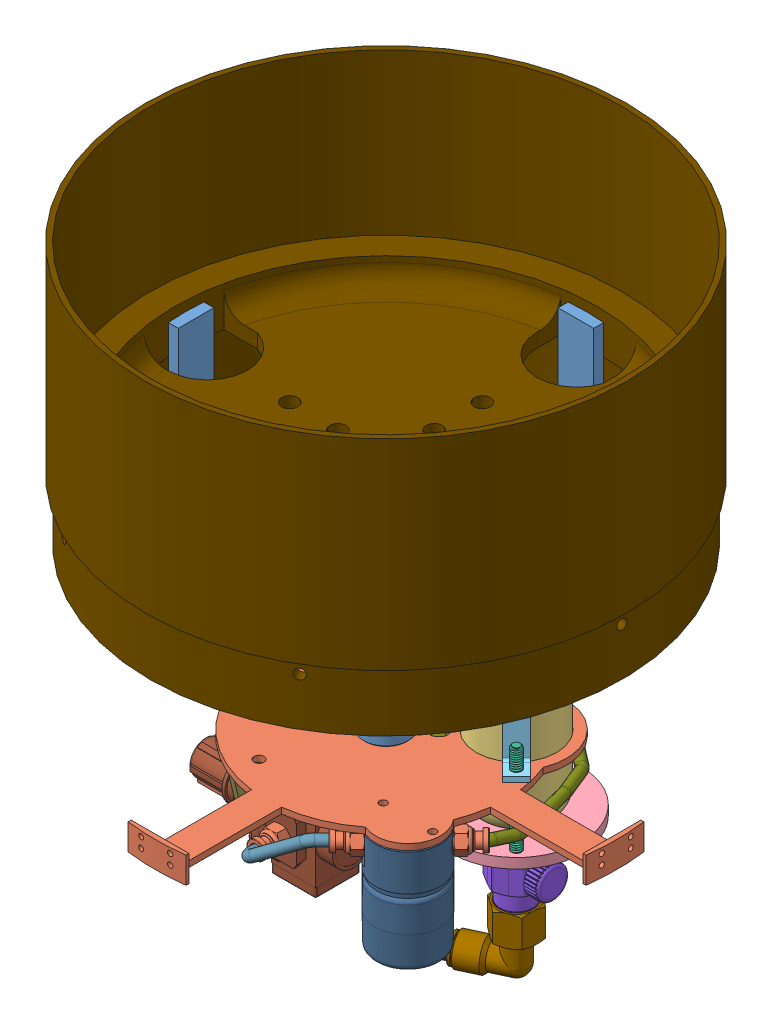
SolidWorks assembly 10004-R01_RECOVERY_SYSTEM, configuration Default. Lengths in mm.
Overall size (304.8 403.35 304.8).
35 component instances, 21 part files, 66 mates.
Components (placement in the parent):
- 16007-RO01_ROUND_BODY_AIR_CYLINDER-2: 16007-RO01_ROUND_BODY_AIR_CYLINDER [6498K062] at (101.6 47.752 101.6) x (0 -1 0) z (-0.809092 0 -0.587682) size (127.62 28.45 28.45)
- 16002-R01_BRASS_PUSH_TO_CONNECT_TUBE_FITTING_FOR_AIR (1)-1: 16002-R01_BRASS_PUSH_TO_CONNECT_TUBE_FITTING_FOR_AIR (1) [51025K177] at (86.3697 13.462 90.5375) x (-0.809092 0 -0.587682) z (-0.508948 -0.5 0.700694) size (22.87 14.66 12.7)
- 14019-R01_RECOVERY_PRESSURE_TANK (1)-1: 14019-R01_RECOVERY_PRESSURE_TANK (1) [Default] at (142.875 76.454 60.325) x (-0.286418 0 0.958105) z (0.958105 0 0.286418) size (50 133 50)
- 14020-R01_RECOVERY_PRESSURE_TANK_BULKHEAD (1)-7: 14020-R01_RECOVERY_PRESSURE_TANK_BULKHEAD (1) [Default] at (142.875 -41.1336 60.325) x (-0.707107 0 -0.707107) z (0.707107 0 -0.707107) size (82.15 6.35 82.15)
- 14021-R01_RECOVERY_PRESSURE_TANK__MOUNT-1: 14021-R01_RECOVERY_PRESSURE_TANK__MOUNT [Default] at (167.4293 6.35 84.8793) x (0.707107 0 0.707107) z (-0.707107 0 0.707107) size (82.15 73.28 12.7)
- 16005-R01_THREADED ROD-1: 16005-R01_THREADED ROD [98750A021] at (167.4293 -9.3836 84.8793) x (0 1 0) z (0 0 1) size (64.96 6.43 6.7)
- 16005-R01_THREADED ROD-2: 16005-R01_THREADED ROD [98750A021] at (118.3207 -9.3836 35.7707) x (0 1 0) z (0 0 1) size (64.96 6.43 6.7)
- 16005-R01_THREADED ROD-3: 16005-R01_THREADED ROD [98750A021] at (118.3207 -9.3836 84.8793) x (0 1 0) z (0 0 1) size (64.96 6.43 6.7)
- 16006-R01_NYLON-INSERT_NUTLOCK-1: 16006-R01_NYLON-INSERT_NUTLOCK [97135A210] at (167.4293 9.525 84.8793) x (0.707107 0 0.707107) z (-0.707107 0 0.707107) size (11.11 8.13 12.83) (hidden)
- 16006-R01_NYLON-INSERT_NUTLOCK-2: 16006-R01_NYLON-INSERT_NUTLOCK [97135A210] at (118.3207 6.35 84.8793) x (0.965926 0 -0.258819) z (0.258819 0 0.965926) size (11.11 8.13 12.83)
- 16006-R01_NYLON-INSERT_NUTLOCK-3: 16006-R01_NYLON-INSERT_NUTLOCK [97135A210] at (118.3207 9.525 35.7707) x (0.965926 0 -0.258819) z (0.258819 0 0.965926) size (11.11 8.13 12.83)
- 16010-R01_ON_OFF_VALVE_FOR_RECOVERY_PRESSURE_TANK-1: 16010-R01_ON_OFF_VALVE_FOR_RECOVERY_PRESSURE_TANK [Default] at (142.875 -56.546 60.325) size (40 51.5 30.85)
- 16009-R01_PUSH_TO_CONNECT_TUBE_FITTING_FOR_AIR_90_DEGREE_SWIVEL-1: 16009-R01_PUSH_TO_CONNECT_TUBE_FITTING_FOR_AIR_90_DEGREE_SWIVEL [5225K893] at (142.875 -86.546 60.325) x (0.422618 0 0.906308) z (0 1 0) size (24.39 44.36 43.87)
- 16002-R01_BRASS_PUSH_TO_CONNECT_TUBE_FITTING_FOR_AIR (1)-5: 16002-R01_BRASS_PUSH_TO_CONNECT_TUBE_FITTING_FOR_AIR (1) [51025K177] at (91.275 -29.083 162.3949) x (0 0 1) z (0 -1 0) size (22.87 14.66 12.7)
- 16002-R01_BRASS_PUSH_TO_CONNECT_TUBE_FITTING_FOR_AIR (1)-7: 16002-R01_BRASS_PUSH_TO_CONNECT_TUBE_FITTING_FOR_AIR (1) [51025K177] at (91.275 -29.083 113.1951) x (0 0 -1) z (0.866025 0.5 0) size (22.87 14.66 12.7)
- 16003-R01_SURE-SEAL_STAINLESS STEEL_SOLENOID_VALVE (1)-3: 16003-R01_SURE-SEAL_STAINLESS STEEL_SOLENOID_VALVE (1) [4639K743] at (156.6334 -6.1976 142.7687) x (-0.706999 0 -0.707214) z (-0.707214 0 0.706999) size (69.98 72.57 41.1)
- 16004-R01_AIR_REGULATOR _WITH_BUILT-IN_PRESSURE_GAUGE (1)-3: 16004-R01_AIR_REGULATOR _WITH_BUILT-IN_PRESSURE_GAUGE (1) [8812K51] at (91.275 -29.083 137.795) x (0 0 -1) z (0 -1 0) size (40.79 94 58.3)
- 14022-R01_BRACKET_FOR_AIR_REGULATOR-1: 14022-R01_BRACKET_FOR_AIR_REGULATOR [Default] at (63.5 -29.083 137.795) x (0 -1 0) z (0 0 1) size (50.93 28.57 53.34)
- 16002-R01_BRASS_PUSH_TO_CONNECT_TUBE_FITTING_FOR_AIR (1)-9: 16002-R01_BRASS_PUSH_TO_CONNECT_TUBE_FITTING_FOR_AIR (1) [51025K177] at (174.4053 -6.1976 125.0022) x (0.707214 0 -0.706999) z (0.612279 0.5 0.612466) size (22.87 14.66 12.7)
- 16002-R01_BRASS_PUSH_TO_CONNECT_TUBE_FITTING_FOR_AIR (1)-10: 16002-R01_BRASS_PUSH_TO_CONNECT_TUBE_FITTING_FOR_AIR (1) [51025K177] at (139.6518 -6.1976 159.7451) x (-0.707214 0 0.706999) z (-0.612279 0.5 -0.612466) size (22.87 14.66 12.7)
- 16008-R01_PUSH_TO_CONNECT_TUBE_FITTING_FOR_AIR_STRAIGHT_ADAPTER-2: 16008-R01_PUSH_TO_CONNECT_TUBE_FITTING_FOR_AIR_STRAIGHT_ADAPTER [5779K719] at (92.2124 -79.6146 83.9494) x (-0.906308 0 0.422618) z (0 -1 0) size (16 16 50.04)
- Tube_4-10004-R01_Recovery_System (4)-1: Tube_4-10004-R01_Recovery_System (4) [Default] at origin size (71.08 37.36 56.07)
  - straight fitting-1: straight fitting [.25 TUBE X .25 NPT] at (148.1269 -6.1976 151.2726) x (0.707214 0 -0.706999) z (0.706999 0 0.707214) size (37.85 16.5 14.29) (hidden)
  - Tube-250X020^Tube_4-10004-R01_Recovery_System (4)-1: Tube-250X020^Tube_4-10004-R01_Recovery_System (4) [Tube .250in OD X .020in Wall] at (132.1396 -6.1976 167.255) x (0.577233 0.577409 0.577409) z (-0.707214 0 0.706999) size (39.07 13.45 39.63) (virtual)
- Tube_5-10004-R01_Recovery_System (4)-1: Tube_5-10004-R01_Recovery_System (4) [Default] at origin size (54.15 57.91 51.01)
  - straight fitting-1: straight fitting [.25 TUBE X .25 NPT] at (91.275 -29.083 131.7828) x (0 0 1) z (-1 0 0) size (37.85 16.5 14.29) (hidden)
  - Tube-250X020^Tube_5-10004-R01_Recovery_System (4)-1: Tube-250X020^Tube_5-10004-R01_Recovery_System (4) [Tube .250in OD X .020in Wall] at (91.275 -29.083 109.1768) x (0.707107 0.707107 0) z (0 0 -1) size (37.62 38.95 28.4) (virtual)
- Tube_7-10004-R01_Recovery_System (4)-1: Tube_7-10004-R01_Recovery_System (4) [Default] at origin size (179.67 88.63 166.88)
  - straight fitting-1: straight fitting [.25 TUBE X .25 NPT] at (97.0152 13.462 98.2699) x (0.809092 0 0.587682) z (-0.587682 0 0.809092) size (37.85 16.5 14.29) (hidden)
  - Tube-250X020^Tube_7-10004-R01_Recovery_System (4)-1: Tube-250X020^Tube_7-10004-R01_Recovery_System (4) [Tube .250in OD X .020in Wall] at (78.7249 13.462 84.9847) x (-0.456869 0.628995 0.628995) z (-0.809092 0 -0.587682) size (87.39 43.3 152.94) (virtual)
- Tube_11-10004-R01_Recovery_System (4)-005-1: Tube_11-10004-R01_Recovery_System (4)-005 [Default] at origin size (62.6 58.78 70.76)
  - Tube-500X010_3^Tube_11-10004-R01_Recovery_System (4)-005-1: Tube-500X010_3^Tube_11-10004-R01_Recovery_System (4)-005 [Tube .500in OD X .010in Wall] at (124.2957 -120.546 68.9887) x (0.313146 0.671543 0.671543) z (-0.906308 0 0.422618) size (40.26 42.84 41.75) (virtual)
- 14011-R03_RECOVERY_MOUNTING_PLATE-1: 14011-R03_RECOVERY_MOUNTING_PLATE [Default<As Machined>] at (101.6 146.304 101.6) size (304.8 165.25 304.8)
- 14018-R02_RECOVERY_SYSTEM_PLATE-1: 14018-R02_RECOVERY_SYSTEM_PLATE [Default] at (101.6 89.154 101.6) x (0 0 -1) z (1 0 0) size (254 82.55 254)
- 14022-R02_RECOVERY_SYSTEM_PISTON_MOUNT-1: 14022-R02_RECOVERY_SYSTEM_PISTON_MOUNT [Default] at (101.6 2.54 101.6) x (0 0 -1) z (1 0 0) size (292.1 16.51 292.1)
Mates (geometry in assembly coordinates):
- Concentric3: concentric: cone of 16007-RO01_ROUND_BODY_AIR_CYLINDER-2 through (91.0411 13.462 93.9306) axis (0.809092 0 0.587682); cylinder of 16002-R01_BRASS_PUSH_TO_CONNECT_TUBE_FITTING_FOR_AIR (1)-1 through (86.3697 13.462 90.5375) axis (0.809092 0 0.587682) radius 3.175
- Tangent1: tangent: cylinder of 16007-RO01_ROUND_BODY_AIR_CYLINDER-2 through (101.6 76.454 101.6) axis (0 1 0) radius 14.224; plane of 16002-R01_BRASS_PUSH_TO_CONNECT_TUBE_FITTING_FOR_AIR (1)-1 through (94.4006 13.462 87.3083) normal (0.809092 0 0.587682)
- Coincident12: coincident: plane of 16007-RO01_ROUND_BODY_AIR_CYLINDER-2 through (109.9592 76.454 90.0915) normal (0 1 0); plane of 14019-R01_RECOVERY_PRESSURE_TANK (1)-1 through (142.875 76.454 60.325) normal (0 1 0)
- Concentric53: concentric: circle of 14019-R01_RECOVERY_PRESSURE_TANK (1)-1; circle of 14020-R01_RECOVERY_PRESSURE_TANK_BULKHEAD (1)-7
- Concentric54: concentric: cylinder of 14019-R01_RECOVERY_PRESSURE_TANK (1)-1 through (142.875 -56.546 60.325) axis (0 -1 0) radius 25; cylinder of 14020-R01_RECOVERY_PRESSURE_TANK_BULKHEAD (1)-7 through (142.875 -34.7836 60.325) axis (0 -1 0) radius 18.796
- Tangent15: tangent: torus of 14019-R01_RECOVERY_PRESSURE_TANK (1)-1; circle of 14020-R01_RECOVERY_PRESSURE_TANK_BULKHEAD (1)-7
- Concentric69: concentric: cylinder of 14020-R01_RECOVERY_PRESSURE_TANK_BULKHEAD (1)-7 through (167.4293 -34.7836 84.8793) axis (0 -1 0) radius 3.175; circle of 16005-R01_THREADED ROD-1
- Coincident47: coincident: plane of 14020-R01_RECOVERY_PRESSURE_TANK_BULKHEAD (1)-7 through (142.875 -41.1336 60.325) normal (0 -1 0); plane of 16005-R01_THREADED ROD-1 through (167.4293 -41.1336 84.8793) normal (0 -1 0)
- Concentric70: concentric: cylinder of 14020-R01_RECOVERY_PRESSURE_TANK_BULKHEAD (1)-7 through (118.3207 -34.7836 35.7707) axis (0 -1 0) radius 3.175; circle of 16005-R01_THREADED ROD-2
- Coincident48: coincident: plane of 14020-R01_RECOVERY_PRESSURE_TANK_BULKHEAD (1)-7 through (142.875 -41.1336 60.325) normal (0 -1 0); plane of 16005-R01_THREADED ROD-2 through (118.3207 -41.1336 35.7707) normal (0 -1 0)
- Concentric71: concentric: cylinder of 14020-R01_RECOVERY_PRESSURE_TANK_BULKHEAD (1)-7 through (118.3207 -34.7836 84.8793) axis (0 -1 0) radius 3.175; circle of 16005-R01_THREADED ROD-3
- Coincident49: coincident: plane of 14020-R01_RECOVERY_PRESSURE_TANK_BULKHEAD (1)-7 through (142.875 -41.1336 60.325) normal (0 -1 0); plane of 16005-R01_THREADED ROD-3 through (118.3207 -41.1336 84.8793) normal (0 -1 0)
- Coincident50: coincident: cylinder of 14020-R01_RECOVERY_PRESSURE_TANK_BULKHEAD (1)-7 through (167.4293 -34.7836 84.8793) axis (0 -1 0) radius 3.175; circle of 16006-R01_NYLON-INSERT_NUTLOCK-1
- Coincident51: coincident: plane of 14021-R01_RECOVERY_PRESSURE_TANK__MOUNT-1 through (167.4293 9.525 84.8793) normal (0 1 0); plane of 16006-R01_NYLON-INSERT_NUTLOCK-1 through (173.6265 9.525 86.5398) normal (0 -1 0)
- Parallel10: parallel: plane of 14021-R01_RECOVERY_PRESSURE_TANK__MOUNT-1 through (171.9194 9.525 89.3694) normal (0.707107 0 0.707107); plane of 16006-R01_NYLON-INSERT_NUTLOCK-1 through (169.0898 17.4625 91.0765) normal (0.707107 0 0.707107)
- Concentric72: concentric: circle of 16005-R01_THREADED ROD-2; circle of 16006-R01_NYLON-INSERT_NUTLOCK-3
- Coincident52: coincident: plane of 14021-R01_RECOVERY_PRESSURE_TANK__MOUNT-1 through (167.4293 9.525 84.8793) normal (0 1 0); plane of 16006-R01_NYLON-INSERT_NUTLOCK-3 through (122.8574 9.525 31.2341) normal (0 -1 0)
- Parallel11: parallel: plane of 14021-R01_RECOVERY_PRESSURE_TANK__MOUNT-1 through (113.8306 9.525 31.2806) normal (-0.707107 0 -0.707107); plane of 16006-R01_NYLON-INSERT_NUTLOCK-3 through (116.6602 17.4625 29.5735) normal (-0.707107 0 -0.707107)
- Concentric73: concentric: circle of 16005-R01_THREADED ROD-3; circle of 16006-R01_NYLON-INSERT_NUTLOCK-2
- Parallel12: parallel: plane of 14021-R01_RECOVERY_PRESSURE_TANK__MOUNT-1 through (113.8306 9.525 31.2806) normal (-0.707107 0 -0.707107); plane of 16006-R01_NYLON-INSERT_NUTLOCK-2 through (116.6602 14.2875 78.6821) normal (-0.707107 0 -0.707107)
- Concentric74: concentric: cylinder of 14019-R01_RECOVERY_PRESSURE_TANK (1)-1 through (142.875 -56.546 60.325) axis (0 -1 0) radius 9.325; cylinder of 16010-R01_ON_OFF_VALVE_FOR_RECOVERY_PRESSURE_TANK-1 through (142.875 -86.546 60.325) axis (0 1 0) radius 10.4775
- Coincident54: coincident: plane of 14019-R01_RECOVERY_PRESSURE_TANK (1)-1 through (142.875 -56.546 60.325) normal (0 -1 0); plane of 16010-R01_ON_OFF_VALVE_FOR_RECOVERY_PRESSURE_TANK-1 through (130.375 -56.546 67.5419) normal (0 1 0)
- Concentric76: concentric: cylinder of 16010-R01_ON_OFF_VALVE_FOR_RECOVERY_PRESSURE_TANK-1 through (142.875 -86.546 60.325) axis (0 1 0) radius 10.4775; circle of 16009-R01_PUSH_TO_CONNECT_TUBE_FITTING_FOR_AIR_90_DEGREE_SWIVEL-1
- Coincident57: coincident: plane of 16010-R01_ON_OFF_VALVE_FOR_RECOVERY_PRESSURE_TANK-1 through (142.875 -86.546 60.325) normal (0 -1 0); plane of 16009-R01_PUSH_TO_CONNECT_TUBE_FITTING_FOR_AIR_90_DEGREE_SWIVEL-1 through (142.875 -86.546 60.325) normal (0 1 0)
- Concentric87: concentric: cylinder of 16004-R01_AIR_REGULATOR _WITH_BUILT-IN_PRESSURE_GAUGE (1)-3 through (54.175 -29.083 137.795) axis (1 0 0) radius 14; cylinder of 14022-R01_BRACKET_FOR_AIR_REGULATOR-1 through (66.675 -29.083 137.795) axis (-1 0 0) radius 13.97
- Coincident62: coincident: plane of 16004-R01_AIR_REGULATOR _WITH_BUILT-IN_PRESSURE_GAUGE (1)-3 through (66.675 -12.333 153.0103) normal (-1 0 0); plane of 14022-R01_BRACKET_FOR_AIR_REGULATOR-1 through (66.675 -29.083 137.795) normal (1 0 0)
- Parallel16: parallel: plane of 16004-R01_AIR_REGULATOR _WITH_BUILT-IN_PRESSURE_GAUGE (1)-3 through (79.275 -0.583 151.795) normal (0 1 0); plane of 14022-R01_BRACKET_FOR_AIR_REGULATOR-1 through (92.075 -0.635 137.795) normal (0 -1 0)
- Concentric88: concentric: cylinder of 16002-R01_BRASS_PUSH_TO_CONNECT_TUBE_FITTING_FOR_AIR (1)-5 through (91.275 -29.083 162.3949) axis (0 0 -1) radius 2.3876; circle of 16004-R01_AIR_REGULATOR _WITH_BUILT-IN_PRESSURE_GAUGE (1)-3
- Coincident64: coincident: plane of 16002-R01_BRASS_PUSH_TO_CONNECT_TUBE_FITTING_FOR_AIR (1)-5 through (87.6088 -22.733 157.795) normal (0 0 -1); plane of 16004-R01_AIR_REGULATOR _WITH_BUILT-IN_PRESSURE_GAUGE (1)-3 through (99.4584 -43.083 157.795) normal (0 0 1)
- Parallel17: parallel: plane of 16002-R01_BRASS_PUSH_TO_CONNECT_TUBE_FITTING_FOR_AIR (1)-5 through (87.6088 -35.433 164.3665) normal (0 -1 0); plane of 16004-R01_AIR_REGULATOR _WITH_BUILT-IN_PRESSURE_GAUGE (1)-3 through (99.4584 -43.083 117.795) normal (0 -1 0)
- Concentric89: concentric: cylinder of 16002-R01_BRASS_PUSH_TO_CONNECT_TUBE_FITTING_FOR_AIR (1)-7 through (91.275 -29.083 113.1951) axis (0 0 1) radius 2.3876; circle of 16004-R01_AIR_REGULATOR _WITH_BUILT-IN_PRESSURE_GAUGE (1)-3
- Coincident66: coincident: plane of 16002-R01_BRASS_PUSH_TO_CONNECT_TUBE_FITTING_FOR_AIR (1)-7 through (83.9427 -29.083 117.795) normal (0 0 1); plane of 16004-R01_AIR_REGULATOR _WITH_BUILT-IN_PRESSURE_GAUGE (1)-3 through (99.4584 -43.083 117.795) normal (0 0 -1)
- Parallel18: parallel: plane of 16002-R01_BRASS_PUSH_TO_CONNECT_TUBE_FITTING_FOR_AIR (1)-7 through (94.9412 -35.433 111.2235) normal (0 -1 0); plane of 16004-R01_AIR_REGULATOR _WITH_BUILT-IN_PRESSURE_GAUGE (1)-3 through (99.4584 -43.083 117.795) normal (0 -1 0)
- Concentric95: concentric: circle of 16003-R01_SURE-SEAL_STAINLESS STEEL_SOLENOID_VALVE (1)-3; cylinder of 16002-R01_BRASS_PUSH_TO_CONNECT_TUBE_FITTING_FOR_AIR (1)-10 through (139.6518 -6.1976 159.7451) axis (0.707214 0 -0.706999) radius 3.175
- Coincident69: coincident: plane of 16003-R01_SURE-SEAL_STAINLESS STEEL_SOLENOID_VALVE (1)-3 through (147.6286 -16.1406 161.218) normal (-0.707214 0 0.706999); plane of 16002-R01_BRASS_PUSH_TO_CONNECT_TUBE_FITTING_FOR_AIR (1)-10 through (148.089 -6.1976 161.6785) normal (0.707214 0 -0.706999)
- Parallel20: parallel: plane of 16003-R01_SURE-SEAL_STAINLESS STEEL_SOLENOID_VALVE (1)-3 through (141.8268 -21.2598 127.9575) normal (0 -1 0); plane of 16002-R01_BRASS_PUSH_TO_CONNECT_TUBE_FITTING_FOR_AIR (1)-10 through (135.6656 -12.5476 158.5462) normal (0 -1 0)
- Concentric96: concentric: cylinder of 16002-R01_BRASS_PUSH_TO_CONNECT_TUBE_FITTING_FOR_AIR (1)-9 through (174.4053 -6.1976 125.0022) axis (-0.707214 0 0.706999) radius 3.175; cylinder of 16002-R01_BRASS_PUSH_TO_CONNECT_TUBE_FITTING_FOR_AIR (1)-10 through (139.6518 -6.1976 159.7451) axis (0.707214 0 -0.706999) radius 3.175
- Tangent16: tangent: cylinder of 16003-R01_SURE-SEAL_STAINLESS STEEL_SOLENOID_VALVE (1)-3 through (156.6334 -24.4348 142.7687) axis (0 1 0) radius 20.5296; plane of 16002-R01_BRASS_PUSH_TO_CONNECT_TUBE_FITTING_FOR_AIR (1)-9 through (165.9682 -6.1976 123.0688) normal (-0.707214 0 0.706999)
- Parallel21: parallel: plane of 16003-R01_SURE-SEAL_STAINLESS STEEL_SOLENOID_VALVE (1)-3 through (141.8268 -21.2598 127.9575) normal (0 -1 0); plane of 16002-R01_BRASS_PUSH_TO_CONNECT_TUBE_FITTING_FOR_AIR (1)-9 through (178.3916 -12.5476 126.2011) normal (0 -1 0)
- Distance2: distance = 63.5 mm: plane of 14020-R01_RECOVERY_PRESSURE_TANK_BULKHEAD (1)-7 through (142.875 -41.1336 60.325) normal (0 -1 0); plane of 16008-R01_PUSH_TO_CONNECT_TUBE_FITTING_FOR_AIR_STRAIGHT_ADAPTER-2 through (89.5288 -104.6336 78.1943) normal (0 -1 0)
- Distance3: distance = 25.4 mm: plane of 16008-R01_PUSH_TO_CONNECT_TUBE_FITTING_FOR_AIR_STRAIGHT_ADAPTER-2 through (92.2124 -79.6146 83.9494) normal (-0.906308 0 0.422618); plane of 16009-R01_PUSH_TO_CONNECT_TUBE_FITTING_FOR_AIR_90_DEGREE_SWIVEL-1 through (115.2326 -112.504 73.2149) normal (-0.906308 0 0.422618)
- Coincident77: coincident: plane of 16009-R01_PUSH_TO_CONNECT_TUBE_FITTING_FOR_AIR_90_DEGREE_SWIVEL-1 through (142.875 -86.546 60.325) normal (0.422618 0 0.906308); plane of 16008-R01_PUSH_TO_CONNECT_TUBE_FITTING_FOR_AIR_STRAIGHT_ADAPTER-2 through (92.2124 -79.6146 83.9494) normal (-0.422618 0 -0.906308)
- Angle1: planar angle = 0.174533 rad: plane of 16009-R01_PUSH_TO_CONNECT_TUBE_FITTING_FOR_AIR_90_DEGREE_SWIVEL-1 through (155.4332 -105.746 54.469) normal (0.573576 0 -0.819152); plane of 14021-R01_RECOVERY_PRESSURE_TANK__MOUNT-1 through (171.9194 9.525 80.3892) normal (0.707107 0 -0.707107)
- Concentric99: concentric: circle of 16007-RO01_ROUND_BODY_AIR_CYLINDER-2; circle of 14022-R02_RECOVERY_SYSTEM_PISTON_MOUNT-1
- Coincident88: coincident: plane of 16007-RO01_ROUND_BODY_AIR_CYLINDER-2 through (109.9592 6.35 90.0915) normal (0 -1 0); plane of 14022-R02_RECOVERY_SYSTEM_PISTON_MOUNT-1 through (101.6 6.35 101.6) normal (0 1 0)
- Parallel28: parallel: plane of 14022-R02_RECOVERY_SYSTEM_PISTON_MOUNT-1 through (111.125 6.35 111.125) normal (0 0 1); plane of assembly through (0 0 0) normal (0 0 1)
- Perpendicular1: perpendicular: plane of 14022-R02_RECOVERY_SYSTEM_PISTON_MOUNT-1 through (92.075 6.35 111.125) normal (-1 0 0); plane of assembly through (0 0 0) normal (0 0 1)
- Concentric101: concentric: circle of 16007-RO01_ROUND_BODY_AIR_CYLINDER-2; circle of 14018-R02_RECOVERY_SYSTEM_PLATE-1
- Coincident91: coincident: plane of 16007-RO01_ROUND_BODY_AIR_CYLINDER-2 through (101.6 89.154 101.6) normal (0 1 0); plane of 14018-R02_RECOVERY_SYSTEM_PLATE-1 through (101.6 89.154 101.6) normal (0 -1 0)
- Parallel29: parallel: plane of 14018-R02_RECOVERY_SYSTEM_PLATE-1 through (117.7419 95.504 112.8668) normal (0 0 1); plane of assembly through (0 0 0) normal (0 0 1)
- Perpendicular2: perpendicular: plane of 14018-R02_RECOVERY_SYSTEM_PLATE-1 through (90.3332 95.504 117.7419) normal (-1 0 0); plane of assembly through (0 0 0) normal (0 0 1)
- Concentric102: concentric: circle of 14011-R03_RECOVERY_MOUNTING_PLATE-1; circle of 14018-R02_RECOVERY_SYSTEM_PLATE-1
- Parallel30: parallel: plane of 14011-R03_RECOVERY_MOUNTING_PLATE-1 through (122.7667 155.194 242.8984) normal (-1 0 0); plane of 14018-R02_RECOVERY_SYSTEM_PLATE-1 through (112.8668 95.504 117.7419) normal (1 0 0)
- Distance4: distance = 12.7 mm: plane of 14018-R02_RECOVERY_SYSTEM_PLATE-1 through (101.6 95.504 101.6) normal (0 1 0); plane of 14011-R03_RECOVERY_MOUNTING_PLATE-1 through (101.6 108.204 101.6) normal (0 -1 0)
- Coincident92: coincident: plane of 16003-R01_SURE-SEAL_STAINLESS STEEL_SOLENOID_VALVE (1)-3 through (156.6334 2.54 142.7687) normal (0 1 0); plane of 14022-R02_RECOVERY_SYSTEM_PISTON_MOUNT-1 through (101.6 2.54 101.6) normal (0 -1 0)
- Concentric103: concentric: circle of 16003-R01_SURE-SEAL_STAINLESS STEEL_SOLENOID_VALVE (1)-3; circle of 14022-R02_RECOVERY_SYSTEM_PISTON_MOUNT-1
- Concentric104: concentric: circle of 16003-R01_SURE-SEAL_STAINLESS STEEL_SOLENOID_VALVE (1)-3; circle of 14022-R02_RECOVERY_SYSTEM_PISTON_MOUNT-1
- Coincident95: coincident: plane of 14021-R01_RECOVERY_PRESSURE_TANK__MOUNT-1 through (167.4293 6.35 84.8793) normal (0 -1 0); plane of 14022-R02_RECOVERY_SYSTEM_PISTON_MOUNT-1 through (101.6 6.35 101.6) normal (0 1 0)
- Parallel31: parallel: plane of 14021-R01_RECOVERY_PRESSURE_TANK__MOUNT-1 through (167.4293 6.35 84.8793) normal (0 -1 0); plane of 14022-R02_RECOVERY_SYSTEM_PISTON_MOUNT-1 through (101.6 2.54 101.6) normal (0 -1 0)
- Coincident97: coincident: plane of 14021-R01_RECOVERY_PRESSURE_TANK__MOUNT-1 through (167.4293 9.525 84.8793) normal (0 1 0); plane of 16006-R01_NYLON-INSERT_NUTLOCK-1 through (173.6265 9.525 86.5398) normal (0 -1 0)
- Concentric105: concentric: circle of 14019-R01_RECOVERY_PRESSURE_TANK (1)-1; circle of 14022-R02_RECOVERY_SYSTEM_PISTON_MOUNT-1
- Concentric106: concentric: circle of 16006-R01_NYLON-INSERT_NUTLOCK-2; circle of 14022-R02_RECOVERY_SYSTEM_PISTON_MOUNT-1
- Coincident100: coincident: plane of 16006-R01_NYLON-INSERT_NUTLOCK-2 through (122.8574 6.35 80.3426) normal (0 -1 0); plane of 14022-R02_RECOVERY_SYSTEM_PISTON_MOUNT-1 through (101.6 6.35 101.6) normal (0 1 0)
- Concentric107: concentric: circle of 14021-R01_RECOVERY_PRESSURE_TANK__MOUNT-1; circle of 14022-R02_RECOVERY_SYSTEM_PISTON_MOUNT-1
- Concentric108: concentric: circle of 14021-R01_RECOVERY_PRESSURE_TANK__MOUNT-1; circle of 14022-R02_RECOVERY_SYSTEM_PISTON_MOUNT-1
- Coincident105: coincident: plane of 14022-R01_BRACKET_FOR_AIR_REGULATOR-1 through (66.675 2.54 137.795) normal (0 1 0); plane of 14022-R02_RECOVERY_SYSTEM_PISTON_MOUNT-1 through (101.6 2.54 101.6) normal (0 -1 0)
